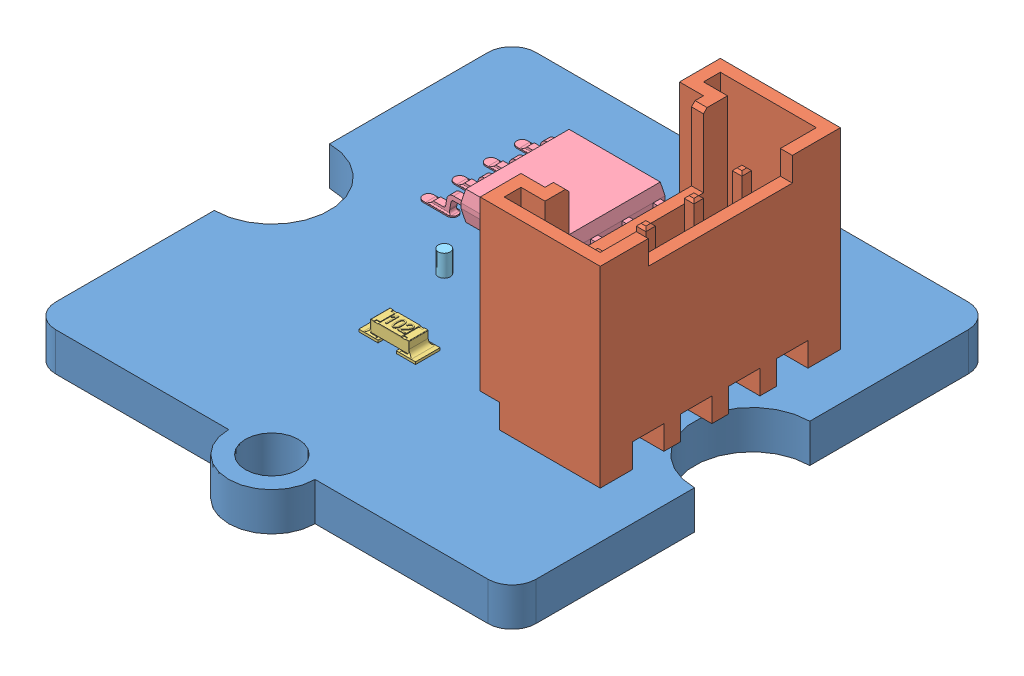
SolidWorks assembly Grove light sensor v1.1, configuration Défaut. Lengths in mm.
Overall size (20 14.6 23.6).
5 component instances, 5 part files, 6 mates.
Components (placement in the parent):
- PCB grove 20x20-1: PCB grove 20x20 [Défaut] at (-7.976 -0.0778 3.7182) size (20 1.6 23.6)
- Connecteur Grove (droit)-2: Connecteur Grove (droit) [Défaut] at (-4.9244 1.5222 3.0954) x (0 0 1) z (-1 0 0) size (10 11 5)
- 603 resistor 102-3: 603 resistor 102 [Default] at (-9.4071 1.5222 6.9759) size (2.36 0.62 1.03)
- LM358-2: LM358 [Default] at (-10.3151 1.5222 -0.7458) size (7.65 1.3 4.5)
- photo Resistor-1: photo Resistor [Défaut] at (-9.6474 -0.0778 3.5967) x (-1 0 0) z (0 0 1) size (4.8 7.5 4.8)
Mates (geometry in assembly coordinates):
- Coïncidente27: coincident anti-aligned: plane of PCB grove 20x20-1 through (-7.976 1.5222 3.7182) normal (0 1 0); plane of Connecteur Grove (droit)-2 through (-4.9244 1.5222 3.0954) normal (0 -1 0)
- Coïncidente28: coincident anti-aligned: plane of PCB grove 20x20-1 through (-7.976 1.5222 3.7182) normal (0 1 0); plane of 603 resistor 102-3 through (-9.4071 1.5222 6.9759) normal (0 -1 0)
- Coïncidente29: coincident anti-aligned: plane of PCB grove 20x20-1 through (-7.976 1.5222 3.7182) normal (0 1 0); plane of LM358-2 through (-7.7151 1.5222 1.2542) normal (0 -1 0)
- Parallèle2: parallel aligned: plane of PCB grove 20x20-1 through (2.024 1.5222 3.7182) normal (1 0 0); plane of Connecteur Grove (droit)-2 through (0.0756 9.5222 -1.9046) normal (1 0 0)
- Parallèle3: parallel: plane of PCB grove 20x20-1 through (-7.976 1.5222 -6.2818) normal (0 0 -1); plane of photo Resistor-1 through (-10.6674 -1.9898 3.4967) normal (0 0 -1)
- Coïncidente33: coincident anti-aligned: plane of PCB grove 20x20-1 through (-7.976 -0.0778 3.7182) normal (0 -1 0); circle of photo Resistor-1
